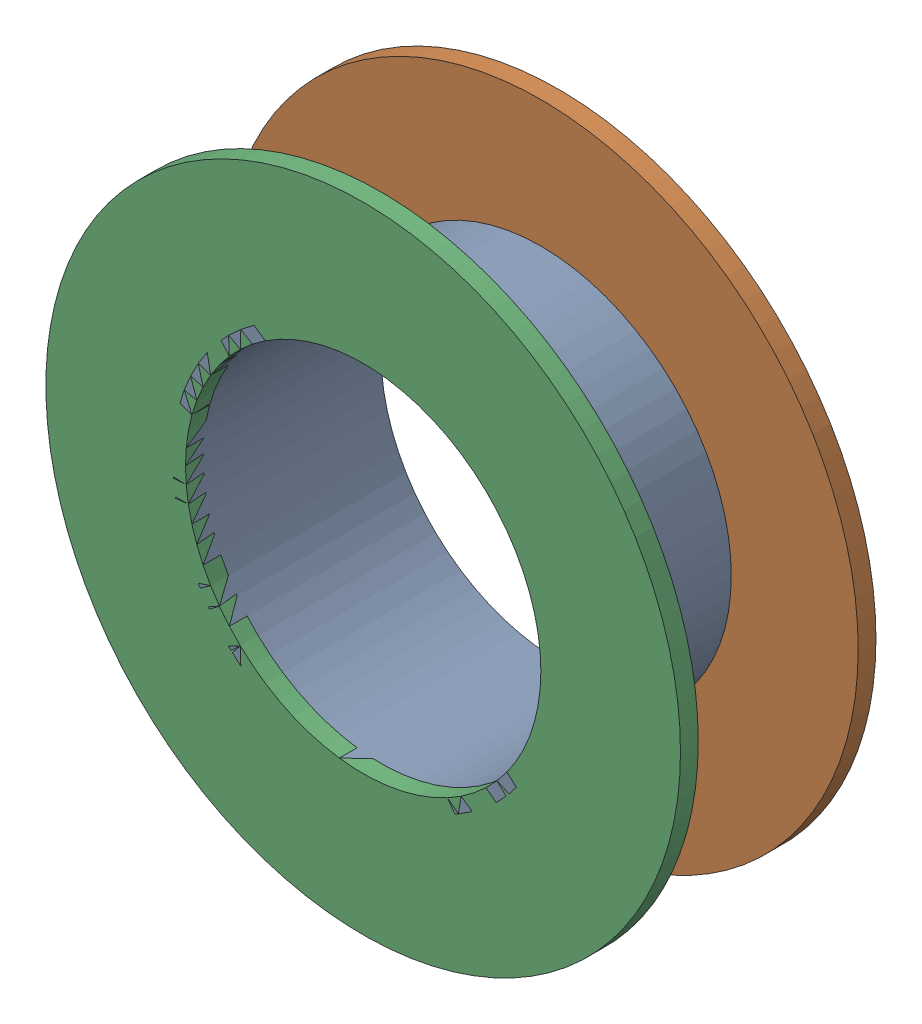
SolidWorks assembly Via (26.1mm,57mm) from Top Layer to Bottom Layer, configuration Predeterminado. Lengths in mm.
Overall size (1.27 1.27 0.39).
6 component instances, 2 part files, 0 mates.
Components (placement in the parent):
- Via Hole-1: Via Hole [Predeterminado] at (26.0999 57.0001 -0.4013) size (0.76 0.76 0.39)
  - Via Hole-Part-1-1: Via Hole-Part-1 [Predeterminado] at origin size (0.76 0.76 0.39)
- Via Top Layer-1: Via Top Layer [Predeterminado] at (26.0999 57.0001 -0.4013) size (1.27 1.27 0.04)
  - Via Top Layer-Part-1-1: Via Top Layer-Part-1 [Predeterminado] at origin size (1.27 1.27 0.04)
- Via Top Layer-2: Via Top Layer [Predeterminado] at (26.0999 57.0001 -0.0457) size (1.27 1.27 0.04)
  - Via Top Layer-Part-1-1: Via Top Layer-Part-1 [Predeterminado] at origin size (1.27 1.27 0.04)
